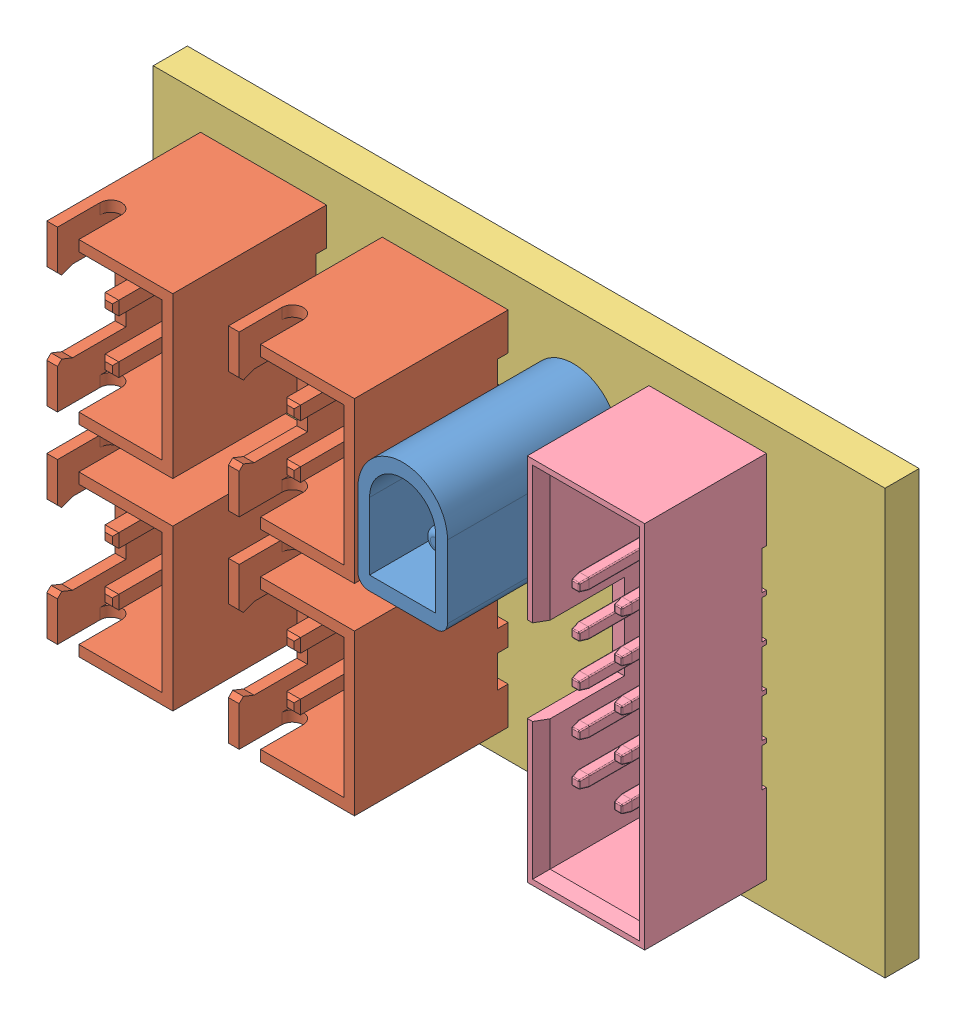
SolidWorks assembly 3D_PCB4_2025-02-06, configuration Default. Lengths in mm.
Overall size (34.28 19.87 11.7).
13 component instances, 4 part files, 0 mates.
Components (placement in the parent):
- 3D_PCB4_2025-02-06.step-1: 3D_PCB4_2025-02-06.step [Default] at origin size (34.28 19.87 11.7)
  - 16c9-CN1-BT2.0.step-1: 16c9-CN1-BT2.0.step [Default] at (-30.4801 31.2421 1.6001) size (4.2 6 11)
    - COMPOUND.step-1: COMPOUND.step [Default] at origin size (4.2 6 11)
  - 16c9-ColdFan-CONN-TH_2P-P2.50_HX25003-2A.step-1: 16c9-ColdFan-CONN-TH_2P-P2.50_HX25003-2A.step [Default] at (-37.3381 29.8451 1.6001) x (0 1 0) z (0 0 1) size (7.5 5.9 10.6)
    - COMPOUND-0.step-1: COMPOUND-0.step [Default] at origin size (7.5 5.9 10.6)
  - 16c9-HotFan-CONN-TH_2P-P2.50_HX25003-2A.step-1: 16c9-HotFan-CONN-TH_2P-P2.50_HX25003-2A.step [Default] at (-45.8471 29.8451 1.6001) x (0 1 0) z (0 0 1) size (7.5 5.9 10.6)
    - COMPOUND-0.step-1: COMPOUND-0.step [Default] at origin size (7.5 5.9 10.6)
  - 16c9-Thermistor-CONN-TH_2P-P2.50_HX25003-2A.step-1: 16c9-Thermistor-CONN-TH_2P-P2.50_HX25003-2A.step [Default] at (-45.8471 20.4172 1.6001) x (0 1 0) z (0 0 1) size (7.5 5.9 10.6)
    - COMPOUND-0.step-1: COMPOUND-0.step [Default] at origin size (7.5 5.9 10.6)
  - 16c9-Klicky-CONN-TH_2P-P2.50_HX25003-2A.step-1: 16c9-Klicky-CONN-TH_2P-P2.50_HX25003-2A.step [Default] at (-37.3381 20.4172 1.6001) x (0 1 0) z (0 0 1) size (7.5 5.9 10.6)
    - COMPOUND-0.step-1: COMPOUND-0.step [Default] at origin size (7.5 5.9 10.6)
  - 16c9-Board.step-1: 16c9-Board.step [Default] at origin size (34.28 19.87 1.6)
  - 16c9-P1-IDC-TH_10P-P2.00-V-R2-C5-S2.00.step-1: 16c9-P1-IDC-TH_10P-P2.00-V-R2-C5-S2.00.step [Default] at (-24.5937 25.0705 1.6001) x (0 -1 0) z (0 0 1) size (17.3 5.5 8.5)
